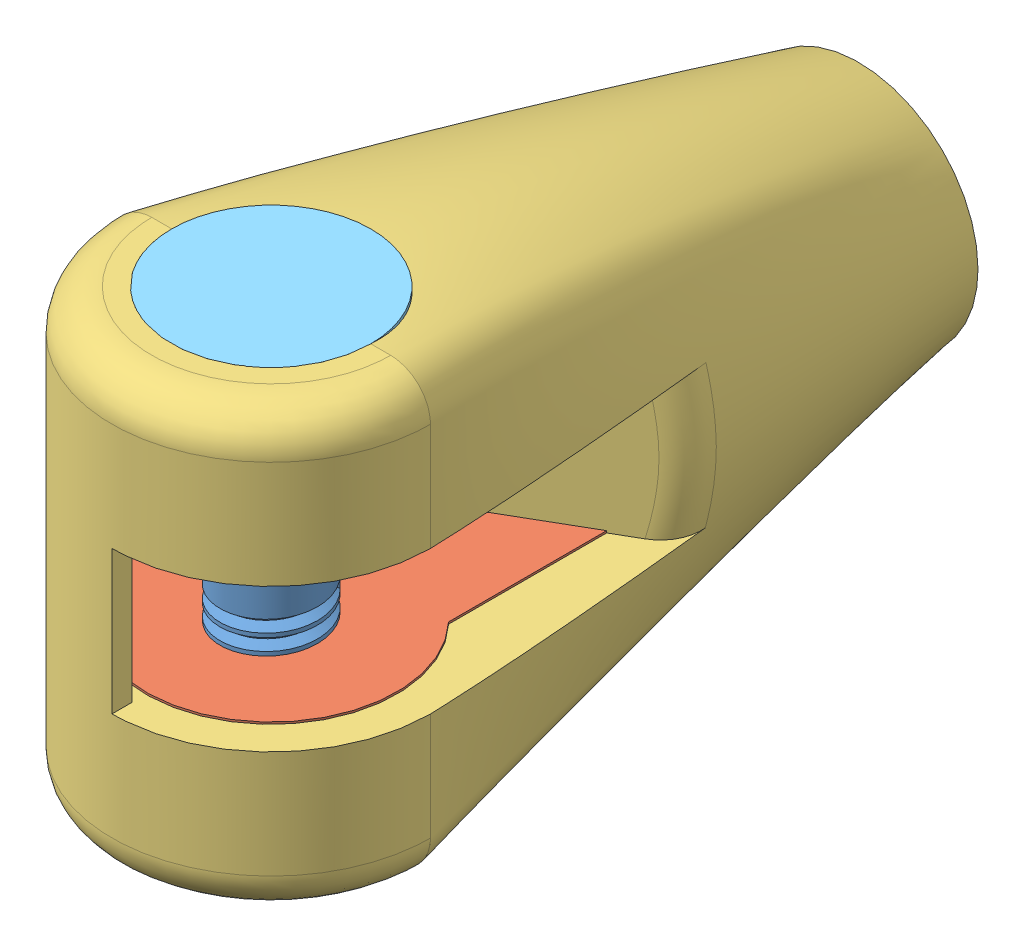
SolidWorks assembly Up Assem, configuration Default. Lengths in mm.
Overall size (21.49 22.29 37.5).
5 component instances, 5 part files, 20 mates.
Components (placement in the parent):
- screw pin-1: screw pin [Default] at (-0.0364 -18.6813 -41.4374) size (7.4 17.79 7.4)
- top metal-1: top metal [Default] at (-0.0364 -26.0313 -70.4903) x (1 0 0) z (0 -1 0) size (12.6 35.35 14.68)
- upper part2-1: upper part2 [Default] at (-0.0364 -26.0313 -70.9374) x (0 1 0) z (1 0 0) size (22.29 37.5 21.49)
- screw pin spacer-1: screw pin spacer [Default] at (-0.0364 -22.4313 -41.4374) x (0 0 1) z (-1 0 0) size (8.08 3.75 7)
- screw cover-1: screw cover [Default] at (-0.0364 -19.0313 -41.4374) size (10 4 10)
Mates (geometry in assembly coordinates):
- Concentric1: concentric anti-aligned: cylinder of ? through (-16.2424 13.8717 3.5944) axis (0 0 -1) radius 2.575; cylinder of ? through (-16.2424 13.8717 -1.9056) axis (0 0 1) radius 5.6
- Distance2: distance = 1 mm aligned: plane of ? through (-15.3768 -4.0158 4.5944) normal (0 0 1); plane of ? through (-19.3424 -0.4283 3.5944) normal (0 0 1)
- Concentric3: concentric aligned: cylinder of ? through (-19.3248 -8.0158 1.3444) axis (0 1 0) radius 2.75; cylinder of ? through (-19.3248 -21.8283 1.3444) axis (0 1 0) radius 2.5
- Parallel1: parallel anti-aligned: plane of ? through (-14.6842 1.0217 1.2637) normal (-0.99985 0 0.017314); plane of ? through (-14.7815 2.5717 3.8636) normal (0.99985 0 -0.017314)
- Coincident3: coincident anti-aligned: plane of ? through (-19.3424 2.5717 1.3444) normal (0 -1 0); plane of ? through (-19.3248 2.5717 1.3444) normal (0 1 0)
- Concentric4: concentric aligned: cylinder of ? through (-16.2424 13.8717 3.5944) axis (0 0 -1) radius 2.575; cylinder of ? through (-16.2424 13.8717 -0.9056) axis (0 0 -1) radius 2.6
- Coincident4: coincident anti-aligned: plane of ? through (-19.3424 -0.4283 -0.9056) normal (0 0 -1); plane of ? through (-16.2424 13.8717 -0.9056) normal (0 0 1)
- Concentric5: concentric anti-aligned: cylinder of ? through (-16.2424 13.8717 3.5944) axis (0 0 -1) radius 2.575; circle of ?
- Coincident5: coincident anti-aligned: plane of ? through (-19.3424 -0.4283 3.5944) normal (0 0 1); plane of ? through (-16.2424 13.8717 3.5944) normal (0 0 -1)
- Concentric6: concentric aligned: cylinder of top metal-1 through (-0.0364 -34.5313 -41.4374) axis (0 1 0) radius 2.1; cylinder of upper part2-1 through (-0.0364 -20.0313 -41.4374) axis (0 1 0) radius 5
- Parallel2: parallel anti-aligned: plane of top metal-1 through (-0.0364 -29.5313 -70.4903) normal (0 1 0); plane of upper part2-1 through (-0.0364 -37.0313 -70.9374) normal (0 -1 0)
- Parallel3: parallel aligned: plane of top metal-1 through (-0.0364 -26.0313 -70.4903) normal (0 0 -1); plane of upper part2-1 through (-0.0364 -26.0313 -70.9374) normal (0 0 -1)
- Concentric7: concentric anti-aligned: cylinder of top metal-1 through (-0.0364 -26.0313 -70.4903) axis (0 0 -1) radius 3.5; circle of upper part2-1
- Concentric8: concentric anti-aligned: cylinder of screw pin-1 through (-0.0364 -33.6813 -41.4374) axis (0 1 0) radius 2.45; cylinder of screw pin spacer-1 through (-0.0364 -12.4313 -41.4374) axis (0 -1 0) radius 2.55
- Coincident8: coincident anti-aligned: plane of screw pin-1 through (-0.0364 -18.6813 -41.4374) normal (0 -1 0); plane of screw pin spacer-1 through (-0.0364 -18.6813 -41.4374) normal (0 1 0)
- Concentric9: concentric aligned: cylinder of screw pin-1 through (-0.0364 -33.6813 -41.4374) axis (0 1 0) radius 2.45; cylinder of upper part2-1 through (-0.0364 -20.0313 -41.4374) axis (0 1 0) radius 5
- Parallel4: parallel anti-aligned: line of upper part2-1 through (-0.0364 -22.4313 -45.7676) axis (-0.866025 0 0.5); line of screw pin spacer-1 through (-0.0364 -22.4313 -37.396) axis (0.866025 0 -0.5)
- Coincident11: coincident aligned: plane of upper part2-1 through (-0.0364 -22.4313 -70.9374) normal (0 -1 0); plane of screw pin spacer-1 through (-0.0364 -22.4313 -41.4374) normal (0 -1 0)
- Concentric10: concentric anti-aligned: cylinder of upper part2-1 through (-0.0364 -20.0313 -41.4374) axis (0 1 0) radius 5; cylinder of screw cover-1 through (-0.0364 -16.0313 -41.4374) axis (0 -1 0) radius 4.9
- Coincident12: coincident aligned: plane of upper part2-1 through (-0.0364 -15.0313 -70.9374) normal (0 1 0); plane of screw cover-1 through (-0.0364 -15.0313 -41.4374) normal (0 1 0)
